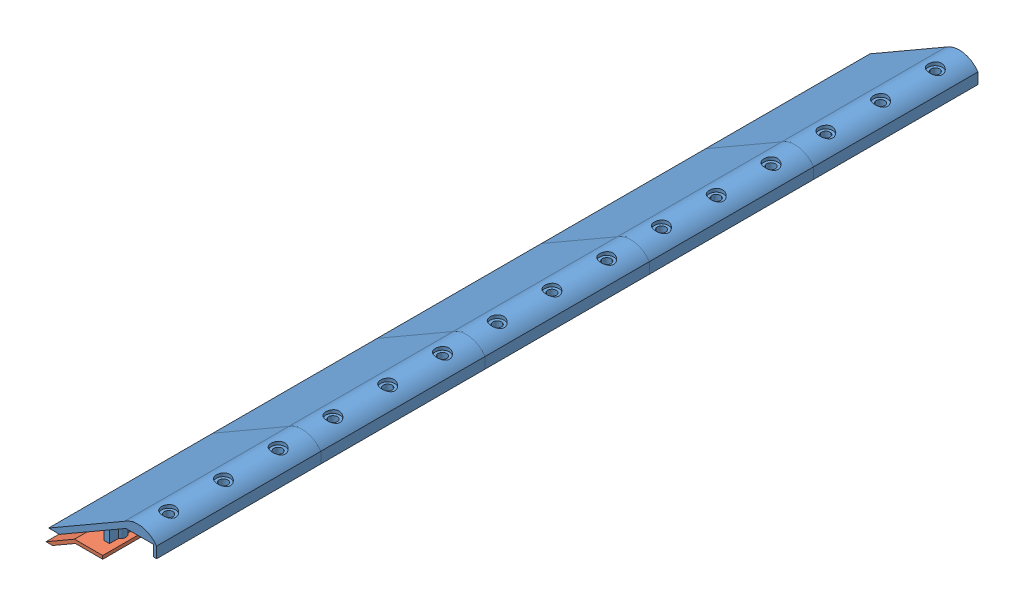
SolidWorks assembly Pala Final, configuration Predeterminado. Lengths in mm.
Overall size (135.72 55.88 750).
15 component instances, 2 part files, 12 mates.
Components (placement in the parent):
- SoportePala-1: SoportePala [Predeterminado] at (-102.2251 6.5255 0) size (135.72 55.88 150)
  - pala2-1: pala2 [Predeterminado] at (85.8775 17.5121 150) size (98.62 43.88 150)
  - protecto pala-1: protecto pala [Predeterminado] at (39.6775 -17.4879 150) size (110.9 15 150)
- SoportePala-2: SoportePala [Predeterminado] at (-102.2251 6.5255 150) size (135.72 55.88 150)
  - pala2-1: pala2 [Predeterminado] at (85.8775 17.5121 150) size (98.62 43.88 150)
  - protecto pala-1: protecto pala [Predeterminado] at (39.6775 -17.4879 150) size (110.9 15 150)
- SoportePala-3: SoportePala [Predeterminado] at (-102.2251 6.5255 300) size (135.72 55.88 150)
  - pala2-1: pala2 [Predeterminado] at (85.8775 17.5121 150) size (98.62 43.88 150)
  - protecto pala-1: protecto pala [Predeterminado] at (39.6775 -17.4879 150) size (110.9 15 150)
- SoportePala-4: SoportePala [Predeterminado] at (-102.2251 6.5255 450) size (135.72 55.88 150)
  - pala2-1: pala2 [Predeterminado] at (85.8775 17.5121 150) size (98.62 43.88 150)
  - protecto pala-1: protecto pala [Predeterminado] at (39.6775 -17.4879 150) size (110.9 15 150)
- SoportePala-5: SoportePala [Predeterminado] at (-102.2251 6.5255 600) size (135.72 55.88 150)
  - pala2-1: pala2 [Predeterminado] at (85.8775 17.5121 150) size (98.62 43.88 150)
  - protecto pala-1: protecto pala [Predeterminado] at (39.6775 -17.4879 150) size (110.9 15 150)
Mates (geometry in assembly coordinates):
- Coincidente1: coincident: plane of SoportePala-1/pala2-1 through (-16.3475 24.0375 225) normal (0 0 1); plane of SoportePala-2/pala2-1 through (-16.3475 24.0375 225) normal (0 0 -1)
- Coincidente2: coincident: plane of SoportePala-1/pala2-1 through (-18.8475 28.3677 225) normal (-0.5 0.866025 0); plane of SoportePala-2/pala2-1 through (-18.8475 28.3677 375) normal (-0.5 0.866025 0)
- Coincidente3: coincident aligned: plane of SoportePala-1/pala2-1 through (-16.3475 -10.9625 225) normal (0 -1 0); plane of SoportePala-2/pala2-1 through (-16.3475 -10.9625 375) normal (0 -1 0)
- Coincidente4: coincident: plane of SoportePala-2/pala2-1 through (-16.3475 24.0375 375) normal (0 0 1); plane of SoportePala-3/pala2-1 through (-16.3475 24.0375 375) normal (0 0 -1)
- Coincidente5: coincident: plane of SoportePala-2/pala2-1 through (-18.8475 28.3677 375) normal (-0.5 0.866025 0); plane of SoportePala-3/pala2-1 through (-18.8475 28.3677 525) normal (-0.5 0.866025 0)
- Coincidente6: coincident aligned: plane of SoportePala-2/pala2-1 through (-16.3475 -10.9625 375) normal (0 -1 0); plane of SoportePala-3/pala2-1 through (-16.3475 -10.9625 525) normal (0 -1 0)
- Coincidente7: coincident: plane of SoportePala-3/pala2-1 through (-16.3475 24.0375 525) normal (0 0 1); plane of SoportePala-4/pala2-1 through (-16.3475 24.0375 525) normal (0 0 -1)
- Coincidente8: coincident: plane of SoportePala-3/pala2-1 through (-18.8475 28.3677 525) normal (-0.5 0.866025 0); plane of SoportePala-4/pala2-1 through (-18.8475 28.3677 675) normal (-0.5 0.866025 0)
- Coincidente9: coincident aligned: plane of SoportePala-3/protecto pala-1 through (-89.3322 -22.9625 525) normal (0 -1 0); plane of SoportePala-4/protecto pala-1 through (-89.3322 -22.9625 675) normal (0 -1 0)
- Coincidente10: coincident: plane of SoportePala-4/pala2-1 through (-16.3475 24.0375 675) normal (0 0 1); plane of SoportePala-5/pala2-1 through (-16.3475 24.0375 675) normal (0 0 -1)
- Coincidente11: coincident: plane of SoportePala-4/pala2-1 through (-18.8475 28.3677 675) normal (-0.5 0.866025 0); plane of SoportePala-5/pala2-1 through (-18.8475 28.3677 825) normal (-0.5 0.866025 0)
- Coincidente12: coincident aligned: plane of SoportePala-4/pala2-1 through (-16.3475 -10.9625 675) normal (0 -1 0); plane of SoportePala-5/pala2-1 through (-16.3475 -10.9625 825) normal (0 -1 0)
